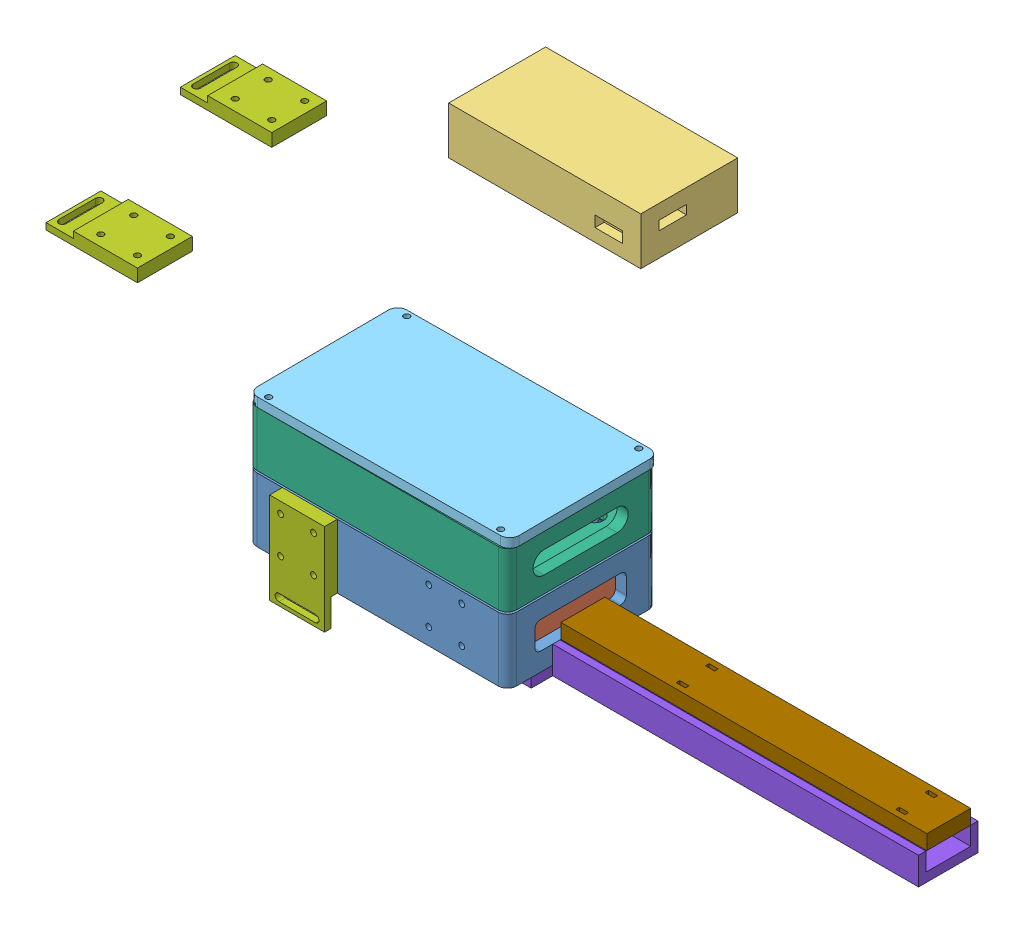
SolidWorks assembly assemble, configuration 默认. Lengths in mm.
Overall size (488.91 147.48 199.79).
12 component instances, 9 part files, 19 mates.
Components (placement in the parent):
- buckler_and_nRF-1: buckler_and_nRF [默认] at (-77.496 -24.777 97.5) size (142 35 82)
- nrfBoard-2: nrfBoard [默认] at (-6.496 -19.777 138.5) size (125 25 63)
- charging_brand-1: charging_brand [默认] at (-107.3984 71.9334 39.7102) size (105 26 53)
- breadboard-1: breadboard [默认] at (12.2717 26.9661 143.1282) x (-0.999962 0 -0.008727) z (0.008727 0 -0.999962) size (81.28 9 53.33)
- uppercover-1: uppercover [默认] at (-6.2549 41.3014 138.0973) x (0.99998 0 -0.006379) z (0.006379 0 0.99998) size (142 5 82)
- upperpart-1: upperpart [默认] at (-6.496 11.3014 138.5) size (142 30 82)
- Side_bar-1: Side_bar [默认] at (-43.496 -14.777 90.5) x (0 1 0) z (1 0 0) size (50 7 30)
- Side_bar-2: Side_bar [默认] at (-43.496 -14.777 186.5) x (0 1 0) z (-1 0 0) size (50 7 30)
- Side_bar-3: Side_bar [默认] at (-199.4033 30.8511 127.8373) size (50 7 30)
- Side_bar-4: Side_bar [默认] at (-156.9566 100.7055 96.8621) size (50 7 30)
- LED_lower-1: LED_lower [默认] at (64.504 -14.777 154.75) x (0 0 -1) z (0 -1 0) size (56 230 15)
- LED_upper-1: LED_upper [默认] at (264.504 -14.777 126.25) x (-1 0 0) z (0 0 -1) size (200 8 24)
Mates (geometry in assembly coordinates):
- Concentric3: concentric aligned: cylinder of buckler_and_nRF-1 through (42.504 -19.777 162.5) axis (0 1 0) radius 1.6; cylinder of nrfBoard-2 through (42.504 5.223 162.5) axis (0 1 0) radius 1.6
- Concentric4: concentric aligned: cylinder of buckler_and_nRF-1 through (-9.996 -19.777 129.5) axis (0 1 0) radius 1.6; cylinder of nrfBoard-2 through (-9.996 5.223 129.5) axis (0 1 0) radius 1.6
- Coincident3: coincident anti-aligned: plane of buckler_and_nRF-1 through (-77.496 -19.777 97.5) normal (0 1 0); plane of nrfBoard-2 through (-6.496 -19.777 138.5) normal (0 -1 0)
- Concentric5: concentric aligned: cylinder of buckler_and_nRF-1 through (-69.496 10.223 100.5) axis (0 1 0) radius 1.6; cylinder of upperpart-1 through (-69.496 41.3014 100.5) axis (0 1 0) radius 1.6
- Concentric6: concentric aligned: cylinder of buckler_and_nRF-1 through (56.504 10.223 176.5) axis (0 1 0) radius 1.6; cylinder of upperpart-1 through (56.504 41.3014 176.5) axis (0 1 0) radius 1.6
- Coincident6: coincident anti-aligned: plane of uppercover-1 through (-6.2549 41.3014 138.0973) normal (0 -1 0); plane of upperpart-1 through (-6.496 41.3014 138.5) normal (0 1 0)
- Concentric7: concentric aligned: cylinder of uppercover-1 through (-69.496 46.3014 100.5) axis (0 1 0) radius 1.6; cylinder of upperpart-1 through (-69.496 41.3014 100.5) axis (0 1 0) radius 1.6
- Coincident7: coincident anti-aligned: plane of buckler_and_nRF-1 through (-77.496 10.223 179.5) normal (0 0 1); plane of Side_bar-2 through (-43.496 -14.777 179.5) normal (0 0 -1)
- Concentric8: concentric aligned: cylinder of buckler_and_nRF-1 through (-52.496 4.223 97.5) axis (0 0 -1) radius 1.6; cylinder of Side_bar-2 through (-52.496 4.223 179.5) axis (0 0 -1) radius 1.6
- Concentric9: concentric aligned: cylinder of buckler_and_nRF-1 through (-34.496 -15.777 97.5) axis (0 0 -1) radius 1.6; cylinder of Side_bar-2 through (-34.496 -15.777 179.5) axis (0 0 -1) radius 1.6
- Coincident9: coincident anti-aligned: plane of buckler_and_nRF-1 through (-77.496 10.223 97.5) normal (0 0 -1); plane of Side_bar-1 through (-43.496 -14.777 97.5) normal (0 0 1)
- Concentric10: concentric anti-aligned: cylinder of buckler_and_nRF-1 through (-52.496 4.223 97.5) axis (0 0 -1) radius 1.6; cylinder of Side_bar-1 through (-52.496 4.223 97.5) axis (0 0 1) radius 1.6
- Concentric11: concentric anti-aligned: cylinder of buckler_and_nRF-1 through (-34.496 -15.777 97.5) axis (0 0 -1) radius 1.6; cylinder of Side_bar-1 through (-34.496 -15.777 97.5) axis (0 0 1) radius 1.6
- Coincident12: coincident anti-aligned: plane of buckler_and_nRF-1 through (-77.496 -24.777 97.5) normal (0 -1 0); plane of LED_lower-1 through (264.504 -24.777 125.2803) normal (0 1 0)
- Coincident13: coincident anti-aligned: plane of LED_lower-1 through (264.504 -14.777 125.2803) normal (0 0 1); plane of LED_upper-1 through (64.504 -6.777 125.2803) normal (0 0 -1)
- Coincident14: coincident anti-aligned: plane of LED_lower-1 through (264.504 -14.777 121.2803) normal (0 1 0); plane of LED_upper-1 through (264.504 -14.777 125.2803) normal (0 -1 0)
- Coincident16: coincident aligned: plane of LED_lower-1 through (264.504 -14.777 153.7803) normal (1 0 0); plane of LED_upper-1 through (264.504 -6.777 125.2803) normal (1 0 0)
- Coincident17: coincident anti-aligned: plane of buckler_and_nRF-1 through (64.504 10.223 97.5) normal (1 0 0); plane of LED_lower-1 through (64.504 -14.777 153.7803) normal (-1 0 0)
- Concentric15: concentric aligned: cylinder of buckler_and_nRF-1 through (41.004 -19.777 114.5) axis (0 1 0) radius 1.6; cylinder of LED_lower-1 through (41.004 -24.777 114.5) axis (0 1 0) radius 1.6
